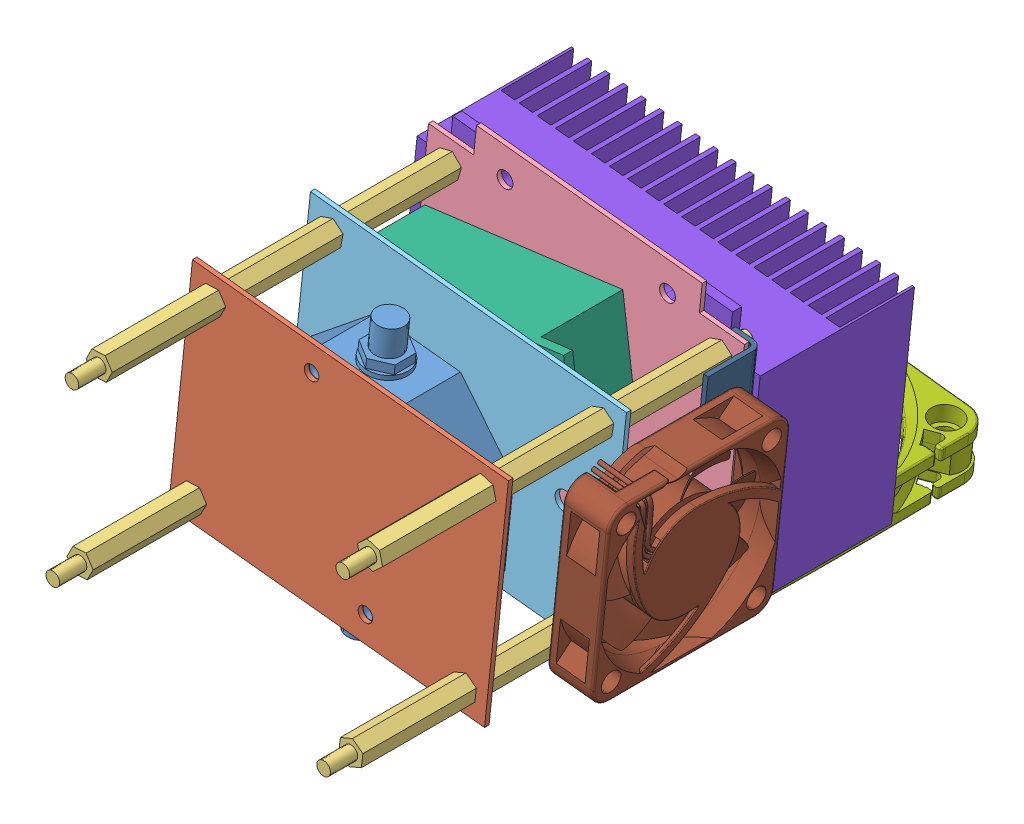
SolidWorks assembly PA_assemb, configuration Default. Lengths in mm.
Overall size (91.16 77.41 148.91).
22 component instances, 11 part files, 0 mates.
Components (placement in the parent):
- signal_combiner-1: signal_combiner [Default] at (-6.6013 7.7255 44.4616) x (0.105435 0.994426 0) z (0 0 1) size (63.1 48.93 14.2)
- signal_combiner_plate-1: signal_combiner_plate [Default] at (-6.6013 7.7255 58.6616) x (0.105435 0.994426 0) z (0 0 1) size (50 70 1)
- copper_pillar_M3_L25-1: copper_pillar_M3_L25 [Default] at (-34.3254 30.777 59.6616) x (0.998791 0.049149 0) z (0.049149 -0.998791 0) size (5.77 37 5)
- copper_pillar_M3_L25-2: copper_pillar_M3_L25 [Default] at (25.3402 24.4509 59.6616) x (0.226101 -0.974104 0) z (-0.974104 -0.226101 0) size (5.77 37 5)
- copper_pillar_M3_L25-3: copper_pillar_M3_L25 [Default] at (21.1228 -15.3261 59.6616) x (0.121779 0.992557 0) z (0.992557 -0.121779 0) size (5.77 37 5)
- copper_pillar_M3_L25-4: copper_pillar_M3_L25 [Default] at (-38.5428 -9 59.6616) x (0.998955 0.045707 0) z (0.045707 -0.998955 0) size (5.77 37 5)
- signal_combiner_plate_1-1: signal_combiner_plate_1 [Default] at (-6.6013 7.7255 6.6616) x (0.105435 0.994426 0) z (0 0 1) size (68 70 1)
- DCDCconvertor_plate-1: DCDCconvertor_plate [Default] at (-6.6013 7.7255 33.6616) x (0.994426 -0.105435 0) z (0 0 -1) size (70 50 1)
- copper_pillar_M3_L25-5: copper_pillar_M3_L25 [Default] at (21.1228 -15.3261 33.6616) x (0.177337 0.98415 0) z (0.98415 -0.177337 0) size (5.77 37 5)
- copper_pillar_M3_L25-6: copper_pillar_M3_L25 [Default] at (-38.5428 -9 33.6616) x (0.177337 0.98415 0) z (0.98415 -0.177337 0) size (5.77 37 5)
- copper_pillar_M3_L25-7: copper_pillar_M3_L25 [Default] at (25.3402 24.4509 33.6616) x (0.168152 0.985761 0) z (0.985761 -0.168152 0) size (5.77 37 5)
- copper_pillar_M3_L25-8: copper_pillar_M3_L25 [Default] at (-34.3254 30.777 33.6616) x (0.179101 0.983831 0) z (0.983831 -0.179101 0) size (5.77 37 5)
- copper_pillar_M3_L25-9: copper_pillar_M3_L25 [Default] at (21.1228 -15.3261 7.6616) x (0.16321 0.986591 0) z (0.986591 -0.16321 0) size (5.77 37 5)
- copper_pillar_M3_L25-10: copper_pillar_M3_L25 [Default] at (25.3402 24.4509 7.6616) x (0.177337 0.98415 0) z (0.98415 -0.177337 0) size (5.77 37 5)
- copper_pillar_M3_L25-11: copper_pillar_M3_L25 [Default] at (-38.5428 -9 7.6616) x (0.278409 0.960462 0) z (0.960462 -0.278409 0) size (5.77 37 5)
- copper_pillar_M3_L25-12: copper_pillar_M3_L25 [Default] at (-34.3254 30.777 7.6616) x (0.276889 0.960902 0) z (0.960902 -0.276889 0) size (5.77 37 5)
- DCDC24Vto15V-1: DCDC24Vto15V [Default] at (-11.2288 16.2477 32.6616) x (0.991678 0.128741 0) z (-0.128741 0.991678 0) size (58 20 24)
- EFB0612HHA-F00-1: EFB0612HHA-F00 [Default] at (-10.397 -28.0739 -27.3384) x (0.994426 -0.105435 0) z (0 0 -1) size (61.81 11.83 61.5)
- N0039 ERAM-0.01-1G-2W-1: N0039 ERAM-0.01-1G-2W [Default] at (-7.023 3.7478 -11.3384) x (0.994426 -0.105435 0) z (-0.105435 -0.994426 0) size (76 34 65)
- fan_fix_plate_connect-1: fan_fix_plate_connect [Default] at (-10.0279 -24.5934 4.6616) x (0.994426 -0.105435 0) z (0 0 -1) size (60 12 12)
- fan_fix_plate_connect2-1: fan_fix_plate_connect2 [Default] at (23.2315 4.5624 5.6616) x (-0.105435 -0.994426 0) z (0 0 1) size (50 12 12)
- CUI_DEVICES_CFM-4010V-150-157-1: CUI_DEVICES_CFM-4010V-150-157 [Default] at (30.1925 3.8244 28.6616) x (-0.105435 -0.994426 0) z (0 0 1) size (40 12.48 40.07)
